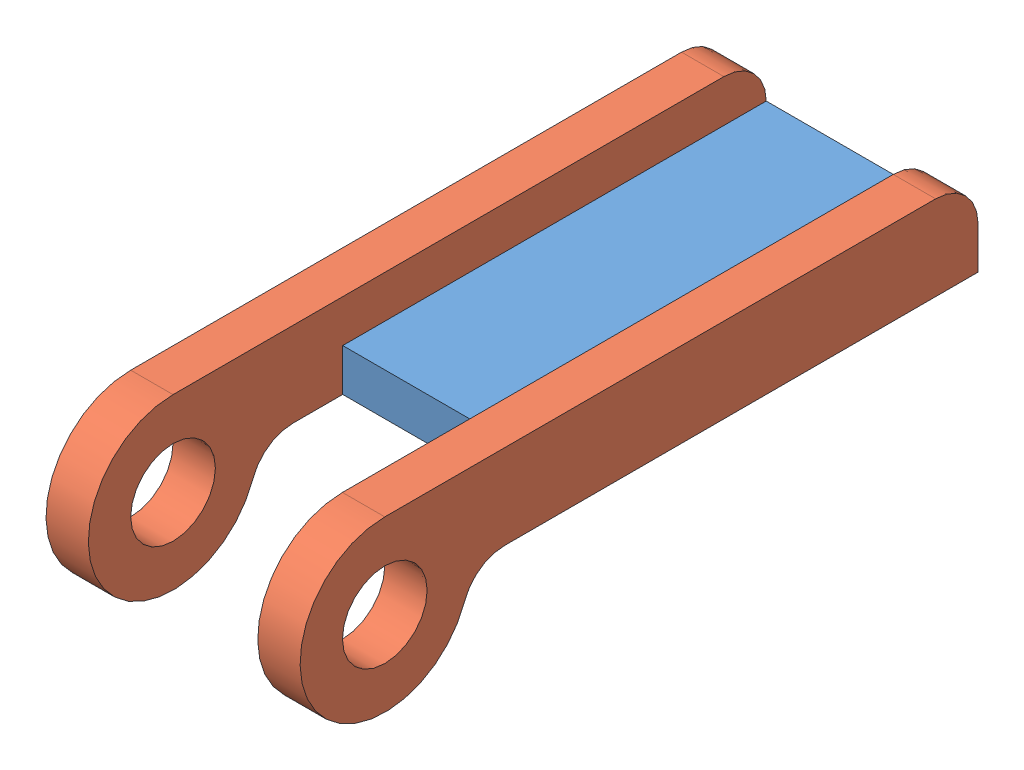
SolidWorks assembly Wing hinge 3, configuration Default. Lengths in mm.
Overall size (19.05 12.7 50.82).
3 component instances, 2 part files, 6 mates.
Components (placement in the parent):
- wing Hinge base-1: wing Hinge base [Default] at (36.8969 16.3027 -10.806) size (12.7 3.17 31.75)
- Trunk Hinge side-1: Trunk Hinge side [Default] at (22.0932 16.3027 51.6907) x (0 0 1) z (-1 0 0) size (50.82 12.7 3.17)
- Trunk Hinge side-2: Trunk Hinge side [Default] at (6.2182 16.3027 51.6907) x (0 0 1) z (-1 0 0) size (50.82 12.7 3.17)
Mates (geometry in assembly coordinates):
- Coincident1: coincident anti-aligned: plane of wing Hinge base-1 through (18.9182 19.4777 7.2199) normal (1 0 0); plane of Trunk Hinge side-1 through (18.9182 16.3027 51.6907) normal (-1 0 0)
- Coincident2: coincident aligned: plane of wing Hinge base-1 through (36.8969 16.3027 -10.806) normal (0 -1 0); plane of Trunk Hinge side-1 through (18.9182 16.3027 51.6907) normal (0 -1 0)
- Coincident3: coincident aligned: plane of wing Hinge base-1 through (6.2182 19.4777 7.2199) normal (0 0 -1); plane of Trunk Hinge side-1 through (18.9182 16.3027 7.2199) normal (0 0 -1)
- Coincident4: coincident anti-aligned: plane of wing Hinge base-1 through (6.2182 19.4777 7.2199) normal (-1 0 0); plane of Trunk Hinge side-2 through (6.2182 16.3027 51.6907) normal (1 0 0)
- Coincident5: coincident aligned: plane of wing Hinge base-1 through (6.2182 19.4777 7.2199) normal (0 0 -1); plane of Trunk Hinge side-2 through (3.0432 16.3027 7.2199) normal (0 0 -1)
- Coincident6: coincident aligned: plane of wing Hinge base-1 through (36.8969 16.3027 -10.806) normal (0 -1 0); plane of Trunk Hinge side-2 through (3.0432 16.3027 51.6907) normal (0 -1 0)
